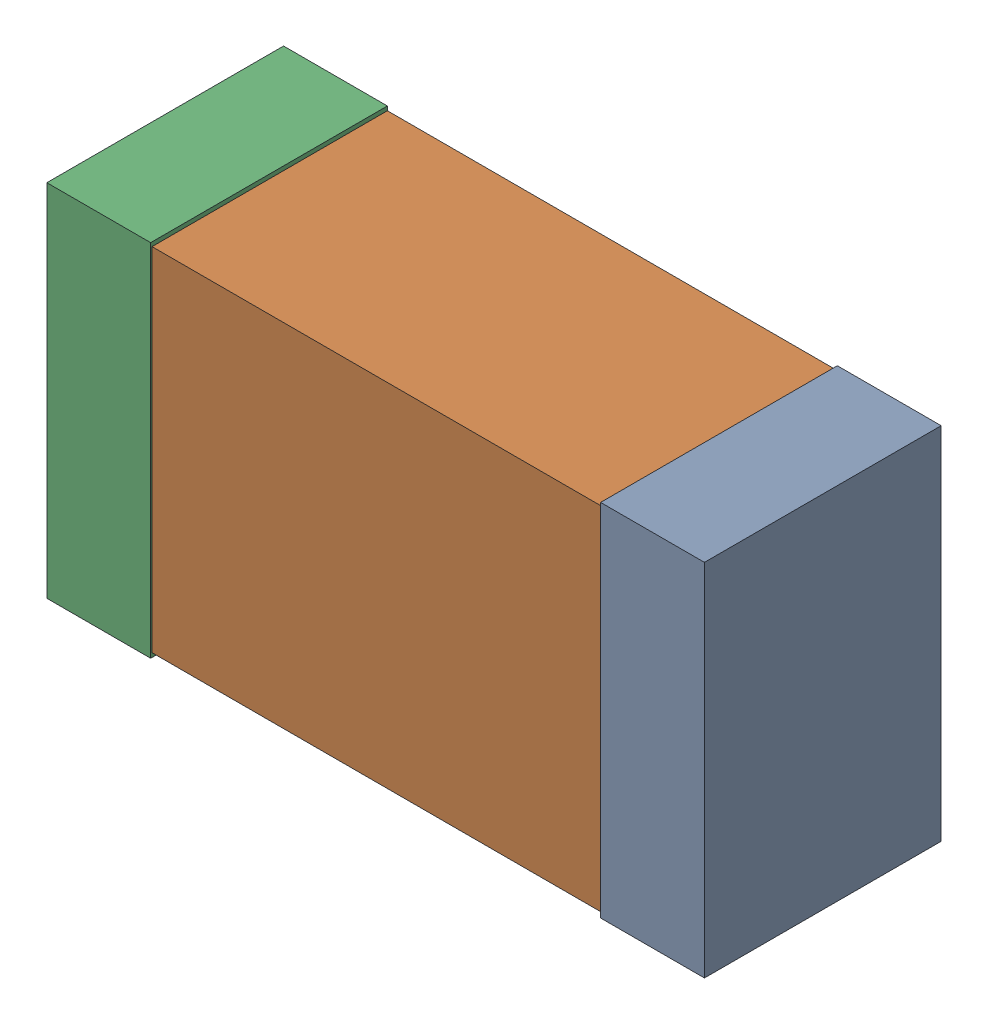
SolidWorks assembly C6Kanaloa_v2.0.0_GPIO_b_1, configuration Default. Lengths in mm.
Overall size (2.38 1.3 0.85).
6 component instances, 2 part files, 0 mates.
Components (placement in the parent):
- 352877648-1: 352877648 [Default] at (144.383 95.123 0) size (0.38 1.3 0.85)
  - Extruded_14-1: Extruded_14 [Default] at origin size (0.38 1.3 0.85)
- 352877904-1: 352877904 [Default] at (143.383 95.123 0) size (2.2 1.27 0.85)
  - Extruded_18-1: Extruded_18 [Default] at origin size (2.2 1.27 0.85)
- 352877648-2: 352877648 [Default] at (142.383 95.123 0) size (0.38 1.3 0.85)
  - Extruded_14-1: Extruded_14 [Default] at origin size (0.38 1.3 0.85)
